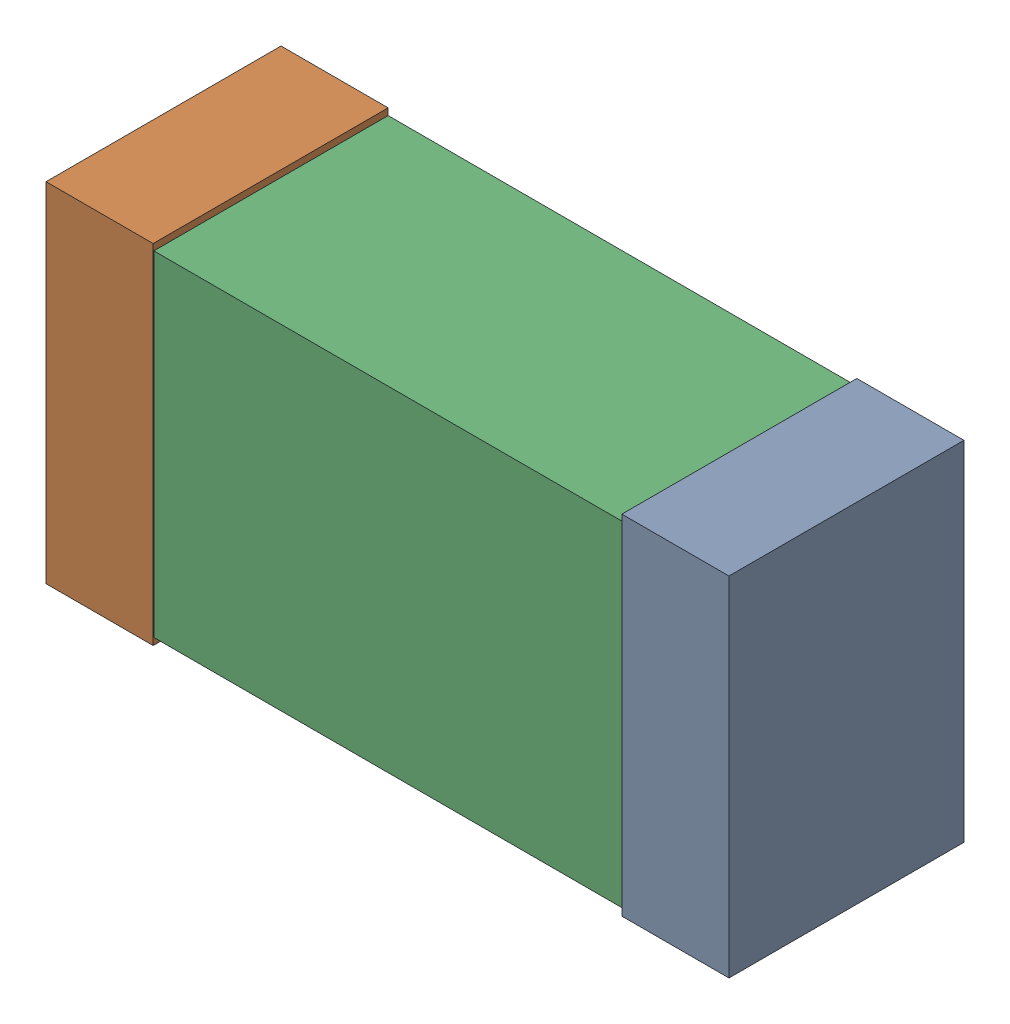
SolidWorks assembly R7, configuration Default. Lengths in mm.
Overall size (1.02 0.52 0.35).
6 component instances, 2 part files, 0 mates.
Components (placement in the parent):
- 870940480-1: 870940480 [Default] at (58.0618 26.4392 0) size (0.16 0.52 0.35)
  - Extruded-1: Extruded [Default] at origin size (0.16 0.52 0.35)
- 870940480-2: 870940480 [Default] at (57.2018 26.4392 0) size (0.16 0.52 0.35)
  - Extruded-1: Extruded [Default] at origin size (0.16 0.52 0.35)
- 870940640-1: 870940640 [Default] at (57.6318 26.4392 0) size (1 0.5 0.35)
  - Extruded_2-1: Extruded_2 [Default] at origin size (1 0.5 0.35)
